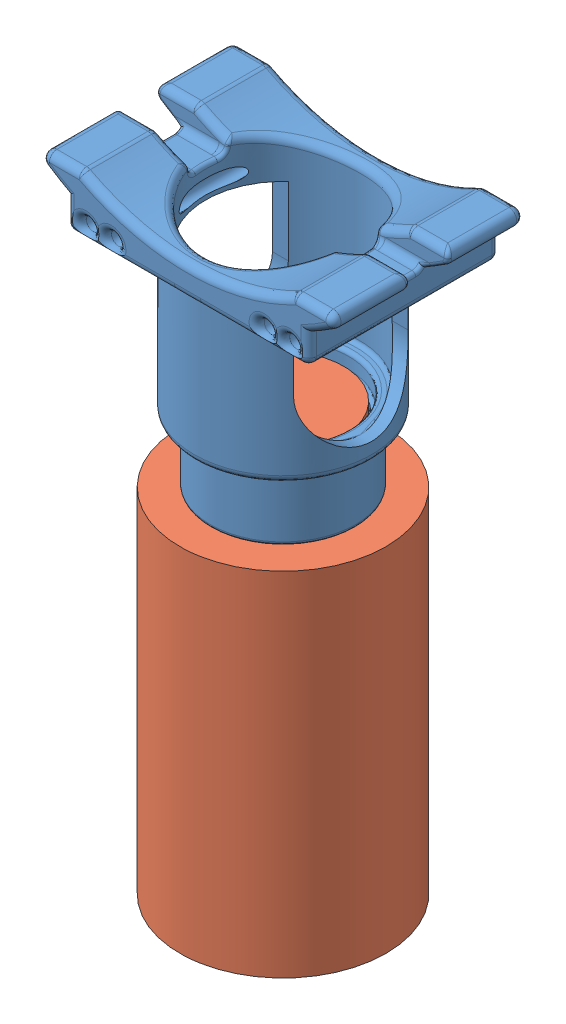
SolidWorks assembly transducer_with_holder_assembly, configuration Default. Lengths in mm.
Overall size (63.5 151.32 59.43).
2 component instances, 2 part files, 2 mates.
Components (placement in the parent):
- transducer_holder-1: transducer_holder [Default] at (47.5834 -47.4533 -16.6486) size (63.5 59.07 50.35)
- transducer-1: transducer [Default] at (47.5834 -139.7033 -16.6486) x (0.994336 0 -0.106287) z (0.106287 0 0.994336) size (54 111.75 54)
Mates (geometry in assembly coordinates):
- Concentric1: concentric anti-aligned: cylinder of transducer_holder-1 through (47.5834 -87.7289 -16.6486) axis (0 1 0) radius 20.25; cylinder of transducer-1 through (47.5834 -27.9533 -16.6486) axis (0 -1 0) radius 15.875
- Coincident1: coincident anti-aligned: plane of transducer_holder-1 through (47.5834 -47.4533 -16.6486) normal (0 -1 0); plane of transducer-1 through (47.5834 -47.4533 -16.6486) normal (0 1 0)
